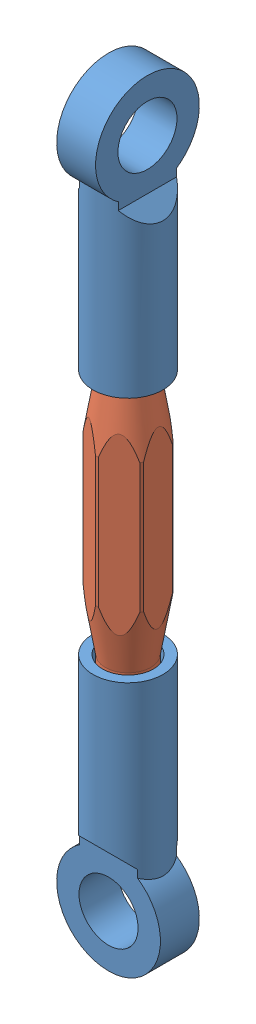
SolidWorks assembly Turnbuckle, configuration Default. Lengths in mm.
Overall size (10.16 75.95 10.16).
3 component instances, 2 part files, 5 mates.
Components (placement in the parent):
- Turnbuckle Eyes-1: Turnbuckle Eyes [Default] at (2.8521 0.9861 23.1995) size (6.86 25.91 10.16)
- Turnbuckle screw-1: Turnbuckle screw [Default] at (2.8521 -11.0789 23.1995) x (0.535456 0 0.844563) z (-0.844563 0 0.535456) size (5.85 35.56 6.83)
- Turnbuckle Eyes-2: Turnbuckle Eyes [Default] at (2.8521 -23.1439 23.1995) x (0 0 1) z (1 0 0) size (6.86 25.91 10.16)
Mates (geometry in assembly coordinates):
- Concentric1: concentric anti-aligned: cylinder of Turnbuckle Eyes-1 through (2.8521 0.9861 23.1995) axis (0 -1 0) radius 2.5; cylinder of Turnbuckle screw-1 through (2.8521 -28.8589 23.1995) axis (0 1 0) radius 2.2371
- Coincident1: coincident anti-aligned: plane of Turnbuckle Eyes-1 through (2.8521 0.9861 23.1995) normal (0 -1 0); circle of Turnbuckle screw-1
- Concentric2: concentric aligned: cylinder of Turnbuckle screw-1 through (2.8521 -28.8589 23.1995) axis (0 1 0) radius 2.2371; cylinder of Turnbuckle Eyes-2 through (2.8521 -23.1439 23.1995) axis (0 1 0) radius 2.5
- Coincident2: coincident aligned: circle of Turnbuckle screw-1; plane of Turnbuckle Eyes-2 through (2.8521 -23.1439 23.1995) normal (0 1 0)
- Perpendicular2: perpendicular: plane of Turnbuckle Eyes-1 through (0.9471 16.8611 19.7705) normal (-1 0 0); plane of Turnbuckle Eyes-2 through (-0.5769 -39.0189 21.2945) normal (0 0 -1)
